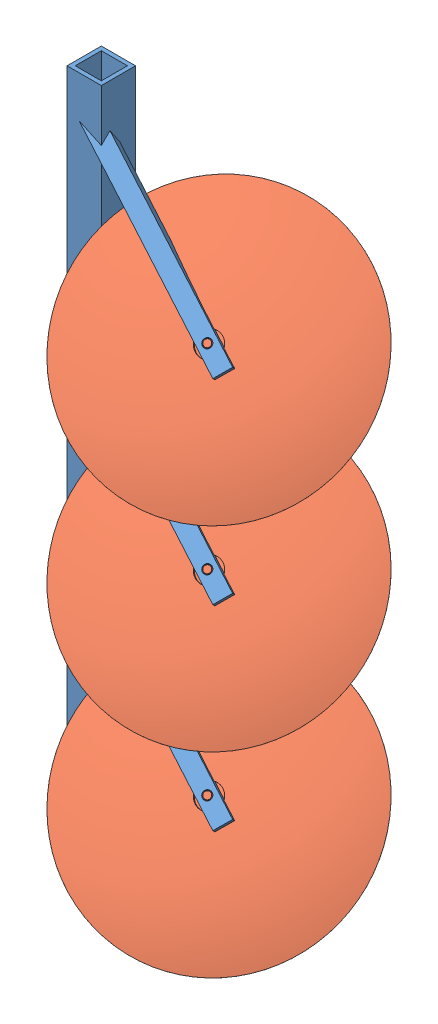
SolidWorks assembly Plough assembly, configuration Default. Lengths in mm.
Overall size (212.01 414.46 172.26).
4 component instances, 2 part files, 5 mates.
Components (placement in the parent):
- base plough-1: base plough [Default] at (310.2557 160.7844 674.4731) size (117.69 400 44.39)
- FRONTAL BLADE SET plough-1: FRONTAL BLADE SET plough [Default] at (290.7636 133.2763 461.7744) x (-0.819348 0.548582 -0.166514) z (-0.313146 -0.671543 -0.671543) size (154.22 154.22 20.07)
- FRONTAL BLADE SET plough-2: FRONTAL BLADE SET plough [Default] at (290.7636 13.2763 461.7744) x (-0.838831 0.527135 -0.135981) z (-0.313146 -0.671543 -0.671543) size (154.22 154.22 20.07)
- FRONTAL BLADE SET plough-3: FRONTAL BLADE SET plough [Default] at (290.7636 -106.7237 461.7744) x (0.745072 0.264754 -0.612187) z (-0.313146 -0.671543 -0.671543) size (154.22 154.22 20.07)
Mates (geometry in assembly coordinates):
- Concentric1: concentric: circle of base plough-1; cylinder of FRONTAL BLADE SET plough-1 through (377.8905 320.1205 648.6186) axis (-0.313146 -0.671543 -0.671543) radius 7
- Concentric2: concentric: cylinder of base plough-1 through (399.6854 246.8599 695.358) axis (0.313146 0.671543 0.671543) radius 2.5; cylinder of FRONTAL BLADE SET plough-2 through (377.8905 200.1205 648.6186) axis (-0.313146 -0.671543 -0.671543) radius 7
- Coincident2: coincident: plane of base plough-1 through (319.4146 300.4256 694.1143) normal (0.313146 0.671543 0.671543); plane of FRONTAL BLADE SET plough-2 through (402.8169 253.5754 702.0734) normal (0.313146 0.671543 0.671543)
- Concentric3: concentric: circle of base plough-1; cylinder of FRONTAL BLADE SET plough-3 through (377.8905 80.1205 648.6186) axis (-0.313146 -0.671543 -0.671543) radius 2
- Coincident3: coincident: plane of base plough-1 through (319.4146 180.4256 694.1143) normal (0.313146 0.671543 0.671543); plane of FRONTAL BLADE SET plough-3 through (402.8169 133.5754 702.0734) normal (0.313146 0.671543 0.671543)
